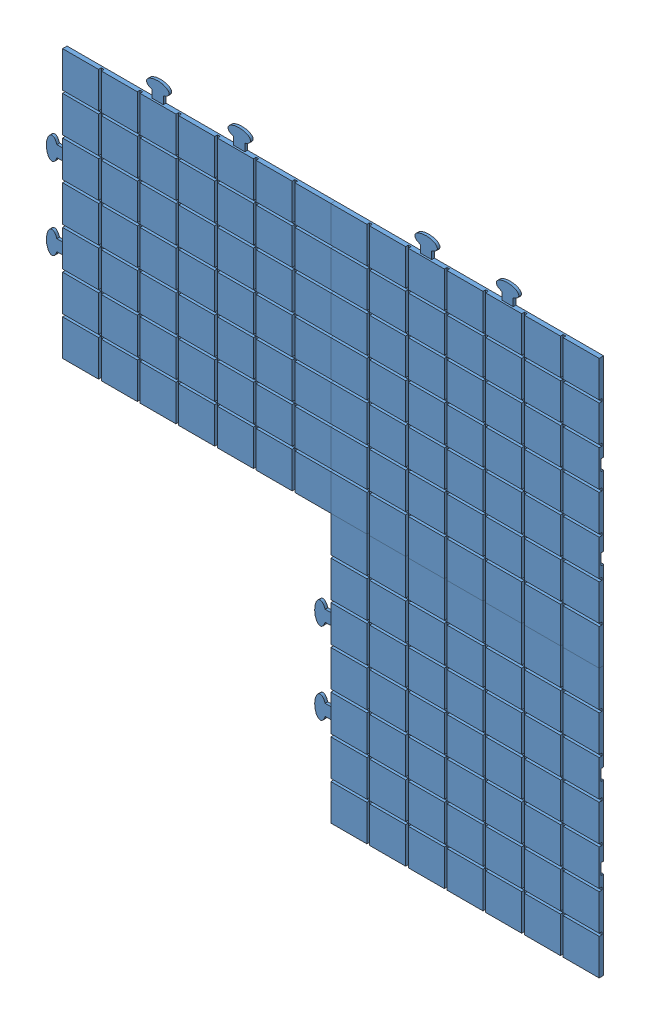
SolidWorks assembly sol_assemble, configuration Défaut. Lengths in mm.
Overall size (616 616 5).
3 component instances, 1 part files, 6 mates.
Components (placement in the parent):
- presque fini-1: presque fini [Défaut] at (42.3664 -22.3185 315.5) size (318 318 5)
- presque fini-2: presque fini [Défaut] at (42.3664 -320.3185 315.5) size (318 318 5)
- presque fini-3: presque fini [Défaut] at (-255.6336 -22.3185 315.5) size (318 318 5)
Mates (geometry in assembly coordinates):
- Coïncidente1: coincident: plane of presque fini-1 through (42.3664 -22.3185 318.5) normal (0 0 -1); plane of presque fini-2 through (42.3664 -320.3185 318.5) normal (0 0 1)
- Coïncidente2: coincident: plane of presque fini-1 through (42.3664 -22.3185 318.5) normal (0 0 1); plane of presque fini-3 through (-255.6336 -22.3185 318.5) normal (0 0 -1)
- Coïncidente3: coincident: plane of presque fini-2 through (-106.6336 -171.3185 320.5) normal (0 1 0); plane of presque fini-1 through (-106.6336 -171.3185 320.5) normal (0 -1 0)
- Coïncidente4: coincident: plane of presque fini-1 through (-106.6336 -171.3185 320.5) normal (-1 0 0); plane of presque fini-3 through (-106.6336 -171.3185 320.5) normal (1 0 0)
- Coïncidente6: coincident: plane of presque fini-1 through (42.3664 29.1815 318.5) normal (0 1 0); plane of presque fini-3 through (-255.6336 29.1815 318.5) normal (0 -1 0)
- Coïncidente7: coincident: plane of presque fini-1 through (-9.1336 -22.3185 318.5) normal (1 0 0); plane of presque fini-2 through (-9.1336 -320.3185 318.5) normal (-1 0 0)
